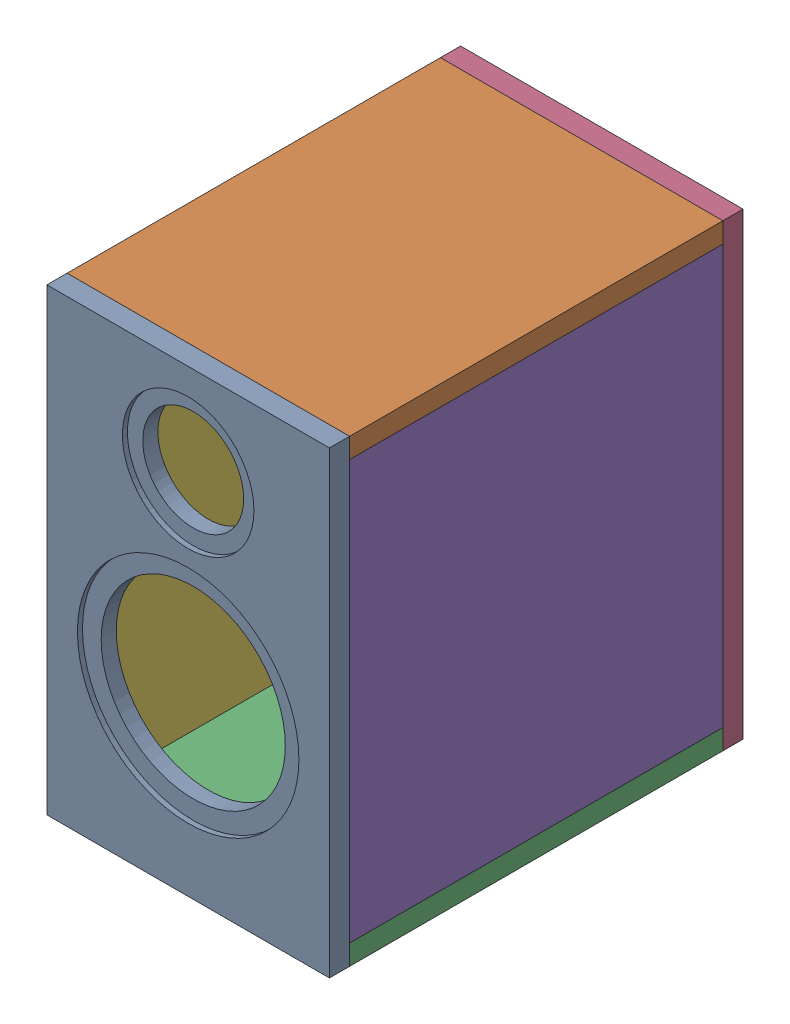
SolidWorks assembly Assem1, configuration Default. Lengths in mm.
Overall size (224 364 328).
6 component instances, 4 part files, 15 mates.
Components (placement in the parent):
- face-1: face [Default] at (-81.251 -18.5095 55.4501) size (224 364 16)
- top_bottom-1: top_bottom [Default] at (-81.251 147.4905 -92.5499) size (224 16 296)
- top_bottom-2: top_bottom [Default] at (-81.251 -200.5095 -92.5499) size (224 16 296)
- back-1: back [Default] at (-81.251 -18.5095 -256.5499) size (224 364 16)
- left_right-1: left_right [Default] at (14.749 -18.5095 -92.5499) size (16 332 296)
- left_right-2: left_right [Default] at (-193.251 -18.5095 -92.5499) size (16 332 296)
Mates (geometry in assembly coordinates):
- Symmetric1: symmetric: plane of face-1 through (30.749 -200.5095 71.4501) normal (1 0 0); plane of ? through (30.749 -184.5095 121.749) normal (1 0 0); plane of top_bottom-1 through (30.749 163.4905 55.4501) normal (1 0 0)
- Coincident2: coincident aligned: plane of face-1 through (30.749 163.4905 71.4501) normal (0 1 0); plane of top_bottom-1 through (113.3386 163.4905 -92.5499) normal (0 1 0)
- Coincident3: coincident anti-aligned: plane of face-1 through (-81.251 -18.5095 55.4501) normal (0 0 -1); plane of top_bottom-1 through (225.3386 163.4905 55.4501) normal (0 0 1)
- Coincident4: coincident aligned: plane of face-1 through (30.749 -200.5095 71.4501) normal (1 0 0); plane of top_bottom-1 through (30.749 163.4905 55.4501) normal (1 0 0)
- Coincident5: coincident: plane of face-1 through (30.749 -200.5095 71.4501) normal (0 -1 0); plane of top_bottom-2 through (-81.251 -200.5095 -92.5499) normal (0 -1 0)
- Coincident6: coincident anti-aligned: plane of face-1 through (-81.251 -18.5095 55.4501) normal (0 0 -1); plane of top_bottom-2 through (30.749 -184.5095 55.4501) normal (0 0 1)
- Coincident7: coincident: plane of top_bottom-1 through (30.749 163.4905 55.4501) normal (1 0 0); plane of back-1 through (30.749 -200.5095 -240.5499) normal (1 0 0)
- Coincident8: coincident: plane of top_bottom-1 through (30.749 163.4905 -240.5499) normal (0 0 -1); plane of back-1 through (-81.251 -18.5095 -240.5499) normal (0 0 1)
- Coincident9: coincident aligned: plane of top_bottom-2 through (-81.251 -200.5095 -92.5499) normal (0 -1 0); plane of back-1 through (30.749 -200.5095 -240.5499) normal (0 -1 0)
- Coincident10: coincident: plane of top_bottom-1 through (30.749 163.4905 55.4501) normal (1 0 0); plane of left_right-1 through (30.749 -18.5095 -92.5499) normal (1 0 0)
- Coincident11: coincident: plane of top_bottom-2 through (-81.251 -184.5095 -92.5499) normal (0 1 0); plane of left_right-1 through (30.749 -184.5095 -240.5499) normal (0 -1 0)
- Coincident12: coincident anti-aligned: plane of face-1 through (-81.251 -18.5095 55.4501) normal (0 0 -1); plane of left_right-1 through (30.749 -184.5095 55.4501) normal (0 0 1)
- Coincident13: coincident: plane of top_bottom-2 through (-81.251 -184.5095 -92.5499) normal (0 1 0); plane of left_right-2 through (-177.251 -184.5095 -240.5499) normal (0 -1 0)
- Coincident14: coincident: plane of face-1 through (-81.251 -18.5095 55.4501) normal (0 0 -1); plane of left_right-2 through (-177.251 -184.5095 55.4501) normal (0 0 1)
- Coincident15: coincident aligned: plane of back-1 through (-193.251 -200.5095 -240.5499) normal (-1 0 0); plane of left_right-2 through (-193.251 -18.5095 -92.5499) normal (-1 0 0)
